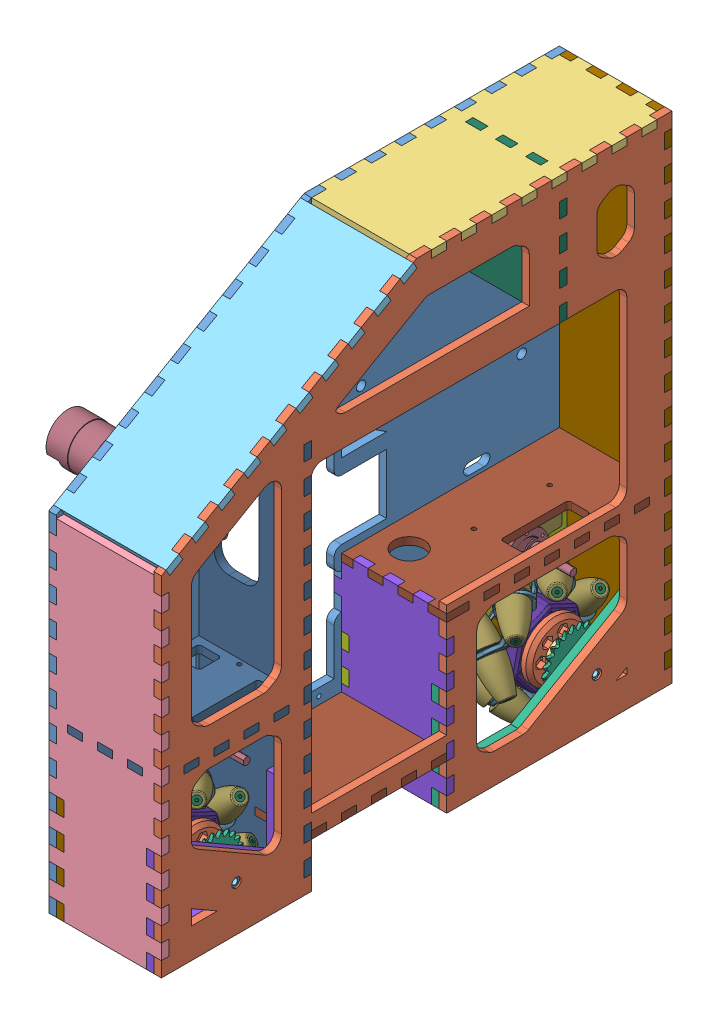
SolidWorks assembly Left Side Assembly, configuration Default. Lengths in mm.
Overall size (177.48 436.49 431.8).
170 component instances, 33 part files, 68 mates.
Components (placement in the parent):
- L Right Panel-1: L Right Panel [Default] at (153.5104 60.089 519.6166) size (6.35 419.1 431.8)
- L Left Panel-1: L Left Panel [Default] at (242.4104 60.089 519.6166) size (6.35 419.1 431.8)
- L Top Panel-1: L Top Panel [Default] at (153.5104 472.839 303.7166) size (95.25 6.35 215.9)
- L Front Panel-1: L Front Panel [Default] at (153.5104 60.089 513.2666) size (95.25 292.1 6.35)
- L Diag Panel-1: L Diag Panel [Default] at (153.5104 351.3271 512.48) x (1 0 0) z (0 0.866025 0.5) size (95.25 241.3 6.35)
- L Mecanum Back Plate A-1: L Mecanum Back Plate A [Default] at (242.4104 60.089 87.8166) x (0 0 1) z (-1 0 0) size (190.5 95.25 6.35)
- L Mecanum Back Plate B-1: L Mecanum Back Plate B [Default] at (166.2104 60.089 87.8166) x (0 0 1) z (-1 0 0) size (190.5 95.25 6.35)
- L Mecanum Front Plate A-1: L Mecanum Front Plate A [Default] at (236.0604 60.089 519.6166) x (0 0 -1) z (1 0 0) size (127 95.25 6.35)
- L Mecanum Front Plate B-1: L Mecanum Front Plate B [Default] at (166.2104 60.089 392.6166) x (0 0 1) z (-1 0 0) size (127 95.25 6.35)
- L Inside Front Panel A-1: L Inside Front Panel A [Default] at (153.5104 60.089 392.6166) size (95.25 355.6 6.35)
- L Bottom Panel-2: L Bottom Panel [Default] at (153.5104 98.189 398.9666) size (95.25 6.35 127)
- Mecanum Left Assembly-1: Mecanum Left Assembly [Default] at (127.408 133.3606 364.6681) x (0 -1 0) z (0 0 1) size (116.24 92.45 118.47)
  - Mecanum Left-1: Mecanum Left [Default] at (35.1717 68.1525 91.4485) size (116.24 62.26 118.47)
    - Roller-1: Roller [Default] at (-8.8714 -0.1061 -39.3041) x (-0.709843 -0.615883 -0.341777) z (0.144671 0.347402 -0.926489) size (22.31 28.6 22.31)
    - Washer-1: Washer [Default] at (-2.1949 -6.9473 -40.8283) x (-0.689398 -0.707107 0.15726) z (0.68937 -0.707107 -0.15738) size (6 6 6.25)
    - Bracket Left-1: Bracket Left [Default] at origin size (28.34 25.51 28.03)
    - Roller Hub-2: Roller Hub [Default] at (25.0439 -0.1061 31.5645) x (0.446415 -0.698084 -0.559815) z (0.703674 -0.112601 0.701544) size (15.2 28.65 15.2)
    - Pin-1: Pin [Default] at (40.2927 0.0354 -0.0424) x (0.491193 -0.615883 -0.615969) z (0.871051 0.347402 0.34725) size (2.6 61.8 2.6)
    - Roller-3: Roller [Default] at (-36.2516 0.1061 17.5878) x (-0.306866 0.707107 -0.637051) z (-0.900888 0.000087 0.434052) size (22.31 28.6 22.31)
    - Washer-2: Washer [Default] at (19.6895 6.9473 -35.8342) x (-0.552772 -0.707107 -0.440957) z (0.552849 -0.707107 0.44086) size (6 6 6.25)
    - Roller-5: Roller [Default] at (25.1987 -0.1061 -31.441) x (-0.175349 -0.615883 -0.768076) z (0.814571 0.347402 -0.464528) size (22.31 28.6 22.31)
    - Washer-5: Washer [Default] at (-33.2899 -6.9473 -23.7392) x (-0.306866 -0.707107 0.637051) z (0.306754 -0.707107 -0.637104) size (6 6 6.25)
    - Bracket Left-2: Bracket Left [Default] x (0.62347 0 -0.781847) z (0.781847 0 0.62347) size (28.34 25.51 28.03)
    - Pin-2: Pin [Default] at (25.1544 0.0354 31.4763) x (0.787838 -0.615883 0) z (0.271578 0.347402 0.897528) size (2.6 61.8 2.6)
    - Roller-6: Roller [Default] at (-36.3528 0.1061 -17.3777) x (0.306754 0.707107 -0.637104) z (-0.901039 0.000087 -0.433738) size (22.31 28.6 22.31)
    - Washer-6: Washer [Default] at (-15.741 6.9473 -37.7357) x (-0.689398 -0.707107 0.15726) z (0.68937 -0.707107 -0.15738) size (6 6 6.25)
    - Roller-9: Roller [Default] at (40.2927 -0.1061 0.099) x (0.491193 -0.615883 -0.615969) z (0.871051 0.347402 0.34725) size (22.31 28.6 22.31)
    - Washer-8: Washer [Default] at (-39.3157 -6.9473 11.2269) x (0.306754 -0.707107 0.637104) z (-0.306866 -0.707107 -0.637051) size (6 6 6.25)
    - Bracket Left-3: Bracket Left [Default] x (-0.22257 0 -0.974917) z (0.974917 0 -0.22257) size (28.34 25.51 28.03)
    - Bracket Left-4: Bracket Left [Default] x (-0.901001 0 -0.433816) z (0.433816 0 -0.901001) size (28.34 25.51 28.03)
    - Roller Hub-6: Roller Hub [Default] at (-36.2516 0.1061 17.5878) x (-0.446512 0.698084 -0.559737) z (-0.840471 -0.112601 0.530028) size (15.2 28.65 15.2)
    - Roller-10: Roller [Default] at (-9.0782 0.1061 -39.2568) x (0.68937 0.707107 -0.15738) z (-0.222655 0.000087 -0.974897) size (22.31 28.6 22.31)
    - Washer-10: Washer [Default] at (-39.3176 6.9473 -11.2201) x (-0.306866 -0.707107 0.637051) z (0.306754 -0.707107 -0.637104) size (6 6 6.25)
    - Roller-13: Roller [Default] at (25.0439 -0.1061 31.5645) x (0.787838 -0.615883 0) z (0.271578 0.347402 0.897528) size (22.31 28.6 22.31)
    - Washer-11: Washer [Default] at (-15.7344 -6.9473 37.7385) x (0.68937 -0.707107 0.15738) z (-0.689398 -0.707107 -0.15726) size (6 6 6.25)
    - Bracket Left-5: Bracket Left [Default] x (-0.900926 0 0.433974) z (-0.433974 0 -0.900926) size (28.34 25.51 28.03)
    - Roller Hub-8: Roller Hub [Default] at (-36.3437 -0.1061 17.3967) x (0.446512 -0.698084 0.559737) z (-0.840471 -0.112601 0.530028) size (15.2 28.65 15.2)
    - Roller-14: Roller [Default] at (25.0329 0.1061 -31.5732) x (0.552849 0.707107 0.44086) z (0.623402 0.000087 -0.781901) size (22.31 28.6 22.31)
    - Washer-14: Washer [Default] at (-33.2858 6.9473 23.745) x (0.306754 -0.707107 0.637104) z (-0.306866 -0.707107 -0.637051) size (6 6 6.25)
    - Roller Hub-11: Roller Hub [Default] at (25.1987 -0.1061 -31.441) x (-0.645131 -0.698084 -0.310619) z (0.527331 -0.112601 -0.842166) size (15.2 28.65 15.2)
    - Roller Hub-12: Roller Hub [Default] at (25.0329 0.1061 -31.5732) x (0.645131 0.698084 0.310619) z (0.527331 -0.112601 -0.842166) size (15.2 28.65 15.2)
    - Pin-5: Pin [Default] at (-8.9197 0.0354 39.293) x (0.491301 -0.615883 0.615883) z (-0.532275 0.347402 0.772007) size (2.6 61.8 2.6)
    - Washer-15: Washer [Default] at (19.6958 -6.9473 35.8307) x (0.552849 -0.707107 -0.44086) z (-0.552772 -0.707107 0.440957) size (6 6 6.25)
    - Bracket Left-6: Bracket Left [Default] x (-0.222399 0 0.974956) z (-0.974956 0 -0.222399) size (28.34 25.51 28.03)
    - Roller Hub-13: Roller Hub [Default] at (40.2927 -0.1061 0.099) x (-0.159363 -0.698084 -0.698056) z (0.98722 -0.112601 -0.112773) size (15.2 28.65 15.2)
    - Roller Hub-14: Roller Hub [Default] at (-36.3528 0.1061 -17.3777) x (0.159242 0.698084 -0.698084) z (-0.938409 -0.112601 -0.326663) size (15.2 28.65 15.2)
    - Roller-17: Roller [Default] at (40.2927 0.1061 -0.1131) x (0 0.707107 0.707107) z (1 0.000087 -0.000087) size (22.31 28.6 22.31)
    - Washer-17: Washer [Default] at (-2.1877 6.9473 40.8287) x (0.68937 -0.707107 0.15738) z (-0.689398 -0.707107 -0.15726) size (6 6 6.25)
    - Roller Hub-17: Roller Hub [Default] at (40.2927 0.1061 -0.1131) x (0.159363 0.698084 0.698056) z (0.98722 -0.112601 -0.112773) size (15.2 28.65 15.2)
    - Pin-7: Pin [Default] at (-36.2823 0.0354 17.5241) x (-0.175215 -0.615883 0.768107) z (-0.935449 0.347402 0.065166) size (2.6 61.8 2.6)
    - Washer-19: Washer [Default] at (40.2939 -6.9473 6.9403) x (0 -0.707107 -0.707107) z (0.000123 -0.707107 0.707107) size (6 6 6.25)
    - Bracket Left-7: Bracket Left [Default] x (0.623607 0 0.781738) z (-0.781738 0 0.623607) size (28.34 25.51 28.03)
    - Roller Hub-18: Roller Hub [Default] at (-36.2608 -0.1061 -17.5689) x (-0.159242 -0.698084 0.698084) z (-0.938409 -0.112601 -0.326663) size (15.2 28.65 15.2)
    - Roller-20: Roller [Default] at (-9.0576 -0.1061 39.2616) x (0.491301 -0.615883 0.615883) z (-0.532275 0.347402 0.772007) size (22.31 28.6 22.31)
    - Washer-20: Washer [Default] at (30.5578 6.9473 27.1659) x (0.552849 -0.707107 -0.44086) z (-0.552772 -0.707107 0.440957) size (6 6 6.25)
    - Pin-9: Pin [Default] at (-36.3221 0.0354 -17.4414) x (-0.709783 -0.615883 0.341901) z (-0.634175 0.347402 -0.690749) size (2.6 61.8 2.6)
    - Hub Inner Left-1: Hub Inner Left [Default] at origin size (62.26 19.81 61.13)
    - Roller Hub-21: Roller Hub [Default] at (-9.0645 -0.1061 39.26) x (0.716016 -0.698084 0) z (-0.109781 -0.112601 0.987557) size (15.2 28.65 15.2)
    - Roller Hub-22: Roller Hub [Default] at (-8.8577 0.1061 39.3072) x (-0.716016 0.698084 0) z (-0.109781 -0.112601 0.987557) size (15.2 28.65 15.2)
    - Roller Hub-23: Roller Hub [Default] at (-9.0782 0.1061 -39.2568) x (0.645077 0.698084 -0.310732) z (-0.329669 -0.112601 -0.937358) size (15.2 28.65 15.2)
    - Roller-22: Roller [Default] at (-36.3437 -0.1061 17.3967) x (-0.175215 -0.615883 0.768107) z (-0.935449 0.347402 0.065166) size (22.31 28.6 22.31)
    - Washer-23: Washer [Default] at (40.2915 6.9473 -6.9544) x (0 -0.707107 -0.707107) z (0.000123 -0.707107 0.707107) size (6 6 6.25)
    - Roller Hub-24: Roller Hub [Default] at (25.2097 0.1061 31.4322) x (-0.446415 0.698084 0.559815) z (0.703674 -0.112601 0.701544) size (15.2 28.65 15.2)
    - Pin-11: Pin [Default] at (-9.0092 0.0354 -39.2726) x (-0.709843 -0.615883 -0.341777) z (0.144671 0.347402 -0.926489) size (2.6 61.8 2.6)
    - Roller-24: Roller [Default] at (25.2152 0.1061 31.4278) x (-0.552772 0.707107 0.440957) z (0.623675 0.000087 0.781684) size (22.31 28.6 22.31)
    - Roller Hub-27: Roller Hub [Default] at (-8.8714 -0.1061 -39.3041) x (-0.645077 -0.698084 0.310732) z (-0.329669 -0.112601 -0.937358) size (15.2 28.65 15.2)
    - Roller-25: Roller [Default] at (-36.2608 -0.1061 -17.5689) x (-0.709783 -0.615883 0.341901) z (-0.634175 0.347402 -0.690749) size (22.31 28.6 22.31)
    - Washer-26: Washer [Default] at (30.553 -6.9473 -27.1713) x (-0.552772 -0.707107 -0.440957) z (0.552849 -0.707107 0.44086) size (6 6 6.25)
    - Hub Outer Left-1: Hub Outer Left [Default] at origin size (61.9 23.71 60.76)
    - Pin-13: Pin [Default] at (25.0881 0.0354 -31.5291) x (-0.175349 -0.615883 -0.768076) z (0.814571 0.347402 -0.464528) size (2.6 61.8 2.6)
    - Roller-28: Roller [Default] at (-8.8508 0.1061 39.3087) x (-0.689398 0.707107 -0.15726) z (-0.222314 0.000087 0.974975) size (22.31 28.6 22.31)
  - Mecanum Hub A-1: Mecanum Hub A [Default] at (35.1717 56.1525 91.4485) x (1 0 0) z (0 -1 0) size (50 50 12)
  - Mecanum Hub B-1: Mecanum Hub B [Default] at (35.1717 80.1525 91.4485) x (1 0 0) z (0 -1 0) size (50 50 12)
  - Tetrix Axle Hub-1: Tetrix Axle Hub [Default] at (35.1717 89.1525 91.4485) x (1 0 0) z (0 -1 0) size (22.1 22.1 9.5)
    - Tetrix Axle Hub Body-1: Tetrix Axle Hub Body [Default] at origin size (22.1 22.1 9.5)
    - Tetrix Axle Hub Set Screw-1: Tetrix Axle Hub Set Screw [Default] at (6.9308 6.9308 -3.325) x (-0.707107 0.707107 0) z (0 0 1) size (4.83 7.94 4.83)
  - Tetrix Axle Hub-2: Tetrix Axle Hub [Default] at (35.1717 47.1525 91.4485) x (1 0 0) z (0 1 0) size (22.1 22.1 9.5)
    - Tetrix Axle Hub Body-1: Tetrix Axle Hub Body [Default] at origin size (22.1 22.1 9.5)
    - Tetrix Axle Hub Set Screw-1: Tetrix Axle Hub Set Screw [Default] at (6.9308 6.9308 -3.325) x (-0.707107 0.707107 0) z (0 0 1) size (4.83 7.94 4.83)
  - Tetrix Bushing Bronze-1: Tetrix Bushing Bronze [Default] at (35.1717 40.4025 91.4485) x (-0.837169 0 -0.546944) z (-0.546944 0 0.837169) size (9.56 12.71 9.56)
  - Tetrix Bushing Bronze-2: Tetrix Bushing Bronze [Default] at (35.1717 104.3025 91.4485) x (-0.837169 0 -0.546944) z (-0.546944 0 0.837169) size (9.56 12.71 9.56)
  - Tetrix Bushing Bronze-3: Tetrix Bushing Bronze [Default] at (35.1717 107.4275 91.4485) x (0.996434 0 -0.084371) z (0.084371 0 0.996434) size (9.56 12.71 9.56)
  - Tetrix Sprocket 24T-1: Tetrix Sprocket 24T [Default] at (35.1717 99.9025 91.4485) x (1 0 0) z (0 -1 0) size (52 52 6.8)
  - Tetrix Axle Spacer Small-1: Tetrix Axle Spacer Small [Default] at (35.1717 105.865 91.4485) x (1 0 0) z (0 -1 0) size (9.5 9.5 3.12)
- Mecanum Left Assembly-2: Mecanum Left Assembly [Default] at (127.408 133.3606 59.8681) x (0 -1 0) z (0 0 1) size (116.24 92.45 118.47)
  - Mecanum Left-1: Mecanum Left [Default] at (35.1717 68.1525 91.4485) size (116.24 62.26 118.47)
    - Roller-1: Roller [Default] at (-8.8714 -0.1061 -39.3041) x (-0.709843 -0.615883 -0.341777) z (0.144671 0.347402 -0.926489) size (22.31 28.6 22.31)
    - Washer-1: Washer [Default] at (-2.1949 -6.9473 -40.8283) x (-0.689398 -0.707107 0.15726) z (0.68937 -0.707107 -0.15738) size (6 6 6.25)
    - Bracket Left-1: Bracket Left [Default] at origin size (28.34 25.51 28.03)
    - Roller Hub-2: Roller Hub [Default] at (25.0439 -0.1061 31.5645) x (0.446415 -0.698084 -0.559815) z (0.703674 -0.112601 0.701544) size (15.2 28.65 15.2)
    - Pin-1: Pin [Default] at (40.2927 0.0354 -0.0424) x (0.491193 -0.615883 -0.615969) z (0.871051 0.347402 0.34725) size (2.6 61.8 2.6)
    - Roller-3: Roller [Default] at (-36.2516 0.1061 17.5878) x (-0.306866 0.707107 -0.637051) z (-0.900888 0.000087 0.434052) size (22.31 28.6 22.31)
    - Washer-2: Washer [Default] at (19.6895 6.9473 -35.8342) x (-0.552772 -0.707107 -0.440957) z (0.552849 -0.707107 0.44086) size (6 6 6.25)
    - Roller-5: Roller [Default] at (25.1987 -0.1061 -31.441) x (-0.175349 -0.615883 -0.768076) z (0.814571 0.347402 -0.464528) size (22.31 28.6 22.31)
    - Washer-5: Washer [Default] at (-33.2899 -6.9473 -23.7392) x (-0.306866 -0.707107 0.637051) z (0.306754 -0.707107 -0.637104) size (6 6 6.25)
    - Bracket Left-2: Bracket Left [Default] x (0.62347 0 -0.781847) z (0.781847 0 0.62347) size (28.34 25.51 28.03)
    - Pin-2: Pin [Default] at (25.1544 0.0354 31.4763) x (0.787838 -0.615883 0) z (0.271578 0.347402 0.897528) size (2.6 61.8 2.6)
    - Roller-6: Roller [Default] at (-36.3528 0.1061 -17.3777) x (0.306754 0.707107 -0.637104) z (-0.901039 0.000087 -0.433738) size (22.31 28.6 22.31)
    - Washer-6: Washer [Default] at (-15.741 6.9473 -37.7357) x (-0.689398 -0.707107 0.15726) z (0.68937 -0.707107 -0.15738) size (6 6 6.25)
    - Roller-9: Roller [Default] at (40.2927 -0.1061 0.099) x (0.491193 -0.615883 -0.615969) z (0.871051 0.347402 0.34725) size (22.31 28.6 22.31)
    - Washer-8: Washer [Default] at (-39.3157 -6.9473 11.2269) x (0.306754 -0.707107 0.637104) z (-0.306866 -0.707107 -0.637051) size (6 6 6.25)
    - Bracket Left-3: Bracket Left [Default] x (-0.22257 0 -0.974917) z (0.974917 0 -0.22257) size (28.34 25.51 28.03)
    - Bracket Left-4: Bracket Left [Default] x (-0.901001 0 -0.433816) z (0.433816 0 -0.901001) size (28.34 25.51 28.03)
    - Roller Hub-6: Roller Hub [Default] at (-36.2516 0.1061 17.5878) x (-0.446512 0.698084 -0.559737) z (-0.840471 -0.112601 0.530028) size (15.2 28.65 15.2)
    - Roller-10: Roller [Default] at (-9.0782 0.1061 -39.2568) x (0.68937 0.707107 -0.15738) z (-0.222655 0.000087 -0.974897) size (22.31 28.6 22.31)
    - Washer-10: Washer [Default] at (-39.3176 6.9473 -11.2201) x (-0.306866 -0.707107 0.637051) z (0.306754 -0.707107 -0.637104) size (6 6 6.25)
    - Roller-13: Roller [Default] at (25.0439 -0.1061 31.5645) x (0.787838 -0.615883 0) z (0.271578 0.347402 0.897528) size (22.31 28.6 22.31)
    - Washer-11: Washer [Default] at (-15.7344 -6.9473 37.7385) x (0.68937 -0.707107 0.15738) z (-0.689398 -0.707107 -0.15726) size (6 6 6.25)
    - Bracket Left-5: Bracket Left [Default] x (-0.900926 0 0.433974) z (-0.433974 0 -0.900926) size (28.34 25.51 28.03)
    - Roller Hub-8: Roller Hub [Default] at (-36.3437 -0.1061 17.3967) x (0.446512 -0.698084 0.559737) z (-0.840471 -0.112601 0.530028) size (15.2 28.65 15.2)
    - Roller-14: Roller [Default] at (25.0329 0.1061 -31.5732) x (0.552849 0.707107 0.44086) z (0.623402 0.000087 -0.781901) size (22.31 28.6 22.31)
    - Washer-14: Washer [Default] at (-33.2858 6.9473 23.745) x (0.306754 -0.707107 0.637104) z (-0.306866 -0.707107 -0.637051) size (6 6 6.25)
    - Roller Hub-11: Roller Hub [Default] at (25.1987 -0.1061 -31.441) x (-0.645131 -0.698084 -0.310619) z (0.527331 -0.112601 -0.842166) size (15.2 28.65 15.2)
    - Roller Hub-12: Roller Hub [Default] at (25.0329 0.1061 -31.5732) x (0.645131 0.698084 0.310619) z (0.527331 -0.112601 -0.842166) size (15.2 28.65 15.2)
    - Pin-5: Pin [Default] at (-8.9197 0.0354 39.293) x (0.491301 -0.615883 0.615883) z (-0.532275 0.347402 0.772007) size (2.6 61.8 2.6)
    - Washer-15: Washer [Default] at (19.6958 -6.9473 35.8307) x (0.552849 -0.707107 -0.44086) z (-0.552772 -0.707107 0.440957) size (6 6 6.25)
    - Bracket Left-6: Bracket Left [Default] x (-0.222399 0 0.974956) z (-0.974956 0 -0.222399) size (28.34 25.51 28.03)
    - Roller Hub-13: Roller Hub [Default] at (40.2927 -0.1061 0.099) x (-0.159363 -0.698084 -0.698056) z (0.98722 -0.112601 -0.112773) size (15.2 28.65 15.2)
    - Roller Hub-14: Roller Hub [Default] at (-36.3528 0.1061 -17.3777) x (0.159242 0.698084 -0.698084) z (-0.938409 -0.112601 -0.326663) size (15.2 28.65 15.2)
    - Roller-17: Roller [Default] at (40.2927 0.1061 -0.1131) x (0 0.707107 0.707107) z (1 0.000087 -0.000087) size (22.31 28.6 22.31)
    - Washer-17: Washer [Default] at (-2.1877 6.9473 40.8287) x (0.68937 -0.707107 0.15738) z (-0.689398 -0.707107 -0.15726) size (6 6 6.25)
    - Roller Hub-17: Roller Hub [Default] at (40.2927 0.1061 -0.1131) x (0.159363 0.698084 0.698056) z (0.98722 -0.112601 -0.112773) size (15.2 28.65 15.2)
    - Pin-7: Pin [Default] at (-36.2823 0.0354 17.5241) x (-0.175215 -0.615883 0.768107) z (-0.935449 0.347402 0.065166) size (2.6 61.8 2.6)
    - Washer-19: Washer [Default] at (40.2939 -6.9473 6.9403) x (0 -0.707107 -0.707107) z (0.000123 -0.707107 0.707107) size (6 6 6.25)
    - Bracket Left-7: Bracket Left [Default] x (0.623607 0 0.781738) z (-0.781738 0 0.623607) size (28.34 25.51 28.03)
    - Roller Hub-18: Roller Hub [Default] at (-36.2608 -0.1061 -17.5689) x (-0.159242 -0.698084 0.698084) z (-0.938409 -0.112601 -0.326663) size (15.2 28.65 15.2)
    - Roller-20: Roller [Default] at (-9.0576 -0.1061 39.2616) x (0.491301 -0.615883 0.615883) z (-0.532275 0.347402 0.772007) size (22.31 28.6 22.31)
    - Washer-20: Washer [Default] at (30.5578 6.9473 27.1659) x (0.552849 -0.707107 -0.44086) z (-0.552772 -0.707107 0.440957) size (6 6 6.25)
    - Pin-9: Pin [Default] at (-36.3221 0.0354 -17.4414) x (-0.709783 -0.615883 0.341901) z (-0.634175 0.347402 -0.690749) size (2.6 61.8 2.6)
    - Hub Inner Left-1: Hub Inner Left [Default] at origin size (62.26 19.81 61.13)
    - Roller Hub-21: Roller Hub [Default] at (-9.0645 -0.1061 39.26) x (0.716016 -0.698084 0) z (-0.109781 -0.112601 0.987557) size (15.2 28.65 15.2)
    - Roller Hub-22: Roller Hub [Default] at (-8.8577 0.1061 39.3072) x (-0.716016 0.698084 0) z (-0.109781 -0.112601 0.987557) size (15.2 28.65 15.2)
    - Roller Hub-23: Roller Hub [Default] at (-9.0782 0.1061 -39.2568) x (0.645077 0.698084 -0.310732) z (-0.329669 -0.112601 -0.937358) size (15.2 28.65 15.2)
    - Roller-22: Roller [Default] at (-36.3437 -0.1061 17.3967) x (-0.175215 -0.615883 0.768107) z (-0.935449 0.347402 0.065166) size (22.31 28.6 22.31)
    - Washer-23: Washer [Default] at (40.2915 6.9473 -6.9544) x (0 -0.707107 -0.707107) z (0.000123 -0.707107 0.707107) size (6 6 6.25)
    - Roller Hub-24: Roller Hub [Default] at (25.2097 0.1061 31.4322) x (-0.446415 0.698084 0.559815) z (0.703674 -0.112601 0.701544) size (15.2 28.65 15.2)
    - Pin-11: Pin [Default] at (-9.0092 0.0354 -39.2726) x (-0.709843 -0.615883 -0.341777) z (0.144671 0.347402 -0.926489) size (2.6 61.8 2.6)
    - Roller-24: Roller [Default] at (25.2152 0.1061 31.4278) x (-0.552772 0.707107 0.440957) z (0.623675 0.000087 0.781684) size (22.31 28.6 22.31)
    - Roller Hub-27: Roller Hub [Default] at (-8.8714 -0.1061 -39.3041) x (-0.645077 -0.698084 0.310732) z (-0.329669 -0.112601 -0.937358) size (15.2 28.65 15.2)
    - Roller-25: Roller [Default] at (-36.2608 -0.1061 -17.5689) x (-0.709783 -0.615883 0.341901) z (-0.634175 0.347402 -0.690749) size (22.31 28.6 22.31)
    - Washer-26: Washer [Default] at (30.553 -6.9473 -27.1713) x (-0.552772 -0.707107 -0.440957) z (0.552849 -0.707107 0.44086) size (6 6 6.25)
    - Hub Outer Left-1: Hub Outer Left [Default] at origin size (61.9 23.71 60.76)
    - Pin-13: Pin [Default] at (25.0881 0.0354 -31.5291) x (-0.175349 -0.615883 -0.768076) z (0.814571 0.347402 -0.464528) size (2.6 61.8 2.6)
    - Roller-28: Roller [Default] at (-8.8508 0.1061 39.3087) x (-0.689398 0.707107 -0.15726) z (-0.222314 0.000087 0.974975) size (22.31 28.6 22.31)
  - Mecanum Hub A-1: Mecanum Hub A [Default] at (35.1717 56.1525 91.4485) x (1 0 0) z (0 -1 0) size (50 50 12)
  - Mecanum Hub B-1: Mecanum Hub B [Default] at (35.1717 80.1525 91.4485) x (1 0 0) z (0 -1 0) size (50 50 12)
  - Tetrix Axle Hub-1: Tetrix Axle Hub [Default] at (35.1717 89.1525 91.4485) x (1 0 0) z (0 -1 0) size (22.1 22.1 9.5)
    - Tetrix Axle Hub Body-1: Tetrix Axle Hub Body [Default] at origin size (22.1 22.1 9.5)
    - Tetrix Axle Hub Set Screw-1: Tetrix Axle Hub Set Screw [Default] at (6.9308 6.9308 -3.325) x (-0.707107 0.707107 0) z (0 0 1) size (4.83 7.94 4.83)
  - Tetrix Axle Hub-2: Tetrix Axle Hub [Default] at (35.1717 47.1525 91.4485) x (1 0 0) z (0 1 0) size (22.1 22.1 9.5)
    - Tetrix Axle Hub Body-1: Tetrix Axle Hub Body [Default] at origin size (22.1 22.1 9.5)
    - Tetrix Axle Hub Set Screw-1: Tetrix Axle Hub Set Screw [Default] at (6.9308 6.9308 -3.325) x (-0.707107 0.707107 0) z (0 0 1) size (4.83 7.94 4.83)
  - Tetrix Bushing Bronze-1: Tetrix Bushing Bronze [Default] at (35.1717 40.4025 91.4485) x (-0.837169 0 -0.546944) z (-0.546944 0 0.837169) size (9.56 12.71 9.56)
  - Tetrix Bushing Bronze-2: Tetrix Bushing Bronze [Default] at (35.1717 104.3025 91.4485) x (-0.837169 0 -0.546944) z (-0.546944 0 0.837169) size (9.56 12.71 9.56)
  - Tetrix Bushing Bronze-3: Tetrix Bushing Bronze [Default] at (35.1717 107.4275 91.4485) x (0.996434 0 -0.084371) z (0.084371 0 0.996434) size (9.56 12.71 9.56)
  - Tetrix Sprocket 24T-1: Tetrix Sprocket 24T [Default] at (35.1717 99.9025 91.4485) x (1 0 0) z (0 -1 0) size (52 52 6.8)
  - Tetrix Axle Spacer Small-1: Tetrix Axle Spacer Small [Default] at (35.1717 105.865 91.4485) x (1 0 0) z (0 -1 0) size (9.5 9.5 3.12)
- L Inside Front Panel B-1: L Inside Front Panel B [Default] at (153.5104 60.089 271.9666) size (95.25 146.05 6.35)
- L Back Panel-2: L Back Panel [Default] at (248.7604 60.089 94.1666) x (-1 0 0) z (0 0 -1) size (95.25 419.1 6.35)
- L Inside Bottom Panel A-1: L Inside Bottom Panel A [Default] at (153.5104 199.789 87.8166) x (0 0 1) z (-1 0 0) size (127 6.35 95.25)
- L Inside Bottom Panel B-1: L Inside Bottom Panel B [Default] at (153.5104 199.789 87.8166) x (0 0 1) z (-1 0 0) size (190.5 6.35 95.25)
- Tetrix Motor Mount-1: Tetrix Motor Mount [Default] at (197.9604 177.289 434.9666) x (0 0 1) z (1 0 0) size (72 45 12.7)
- Tetrix Motor Mount-2: Tetrix Motor Mount [Default] at (197.9604 177.289 172.4666) x (0 0 -1) z (-1 0 0) size (72 45 12.7)
- Tetrix Motor NeveRest (AM-2964)-1: Tetrix Motor NeveRest (AM-2964) [Default] at (184.6604 177.289 434.9666) x (0 1 0) z (1 0 0) size (38 38 133.81)
- Tetrix Motor NeveRest (AM-2964)-2: Tetrix Motor NeveRest (AM-2964) [Default] at (184.6604 177.289 172.4666) x (0 -1 0) z (1 0 0) size (38 38 133.81)
- Tetrix Motor Mount-3: Tetrix Motor Mount [Default] at (166.2104 320.439 421.4666) x (0 1 0) z (1 0 0) size (72 45 12.7)
- Tetrix Motor NeveRest (AM-2964)-3: Tetrix Motor NeveRest (AM-2964) [Default] at (146.5604 320.439 421.4666) x (0 0.171959 0.985104) z (1 0 0) size (38 38 133.81)
- Tetrix Sprocket 16T-1: Tetrix Sprocket 16T [Default] at (185.8704 180.739 491.0416) x (0 0 -1) z (1 0 0) size (36 36 6.8)
- Tetrix Sprocket 24T-1: Tetrix Sprocket 24T [Default] at (185.8704 313.5432 422.6703) x (0 0.679018 0.734122) z (1 0 0) size (52 52 6.8)
- L Servo Mount-2: L Servo Mount [Default] at (248.7604 371.239 183.0666) x (0 0 -1) z (1 0 0) size (6.35 107.95 95.25)
Mates (geometry in assembly coordinates):
- Coincident1: coincident aligned: plane of L Right Panel-1 through (153.5104 60.089 519.6166) normal (-1 0 0); plane of L Top Panel-1 through (153.5104 479.189 303.7166) normal (-1 0 0)
- Coincident2: coincident anti-aligned: plane of L Right Panel-1 through (153.5104 472.839 151.3166) normal (0 1 0); plane of L Top Panel-1 through (153.5104 472.839 303.7166) normal (0 -1 0)
- Coincident3: coincident aligned: plane of L Right Panel-1 through (159.8604 479.189 87.8166) normal (0 0 -1); plane of L Top Panel-1 through (153.5104 479.189 87.8166) normal (0 0 -1)
- Coincident8: coincident anti-aligned: plane of L Left Panel-1 through (242.4104 60.089 519.6166) normal (-1 0 0); plane of L Top Panel-1 through (242.4104 472.839 138.6166) normal (1 0 0)
- Coincident9: coincident aligned: plane of L Left Panel-1 through (248.7604 479.189 303.7166) normal (0 1 0); plane of L Top Panel-1 through (153.5104 479.189 303.7166) normal (0 1 0)
- Coincident11: coincident aligned: plane of L Right Panel-1 through (159.8604 354.539 519.6166) normal (0 0.866025 0.5); plane of L Diag Panel-1 through (153.5104 356.8263 515.655) normal (0 0.866025 0.5)
- Coincident12: coincident anti-aligned: plane of L Left Panel-1 through (242.4104 477.4763 306.683) normal (0 -0.5 0.866025); plane of L Diag Panel-1 through (153.5104 477.4763 306.683) normal (0 0.5 -0.866025)
- Coincident13: coincident aligned: plane of L Left Panel-1 through (248.7604 60.089 519.6166) normal (1 0 0); plane of L Diag Panel-1 through (248.7604 356.8263 515.655) normal (1 0 0)
- Coincident14: coincident aligned: plane of L Left Panel-1 through (248.7604 60.089 519.6166) normal (0 0 1); plane of L Front Panel-1 through (153.5104 60.089 519.6166) normal (0 0 1)
- Coincident15: coincident aligned: plane of L Left Panel-1 through (248.7604 60.089 519.6166) normal (1 0 0); plane of L Front Panel-1 through (248.7604 60.089 519.6166) normal (1 0 0)
- Coincident16: coincident aligned: plane of L Left Panel-1 through (248.7604 60.089 392.6166) normal (0 -1 0); plane of L Front Panel-1 through (153.5104 60.089 519.6166) normal (0 -1 0)
- Coincident17: coincident anti-aligned: plane of L Right Panel-1 through (159.8604 60.089 519.6166) normal (1 0 0); plane of L Mecanum Back Plate B-1 through (159.8604 60.089 87.8166) normal (-1 0 0)
- Coincident20: coincident anti-aligned: plane of L Left Panel-1 through (242.4104 60.089 519.6166) normal (-1 0 0); plane of L Mecanum Back Plate A-1 through (242.4104 60.089 87.8166) normal (1 0 0)
- Coincident21: coincident aligned: plane of L Left Panel-1 through (248.7604 60.089 87.8166) normal (0 -1 0); plane of L Mecanum Back Plate A-1 through (236.0604 60.089 87.8166) normal (0 -1 0)
- Coincident24: coincident anti-aligned: plane of L Left Panel-1 through (242.4104 60.089 519.6166) normal (-1 0 0); plane of L Mecanum Front Plate A-1 through (242.4104 60.089 519.6166) normal (1 0 0)
- Coincident25: coincident aligned: plane of L Left Panel-1 through (248.7604 60.089 392.6166) normal (0 -1 0); plane of L Mecanum Front Plate A-1 through (242.4104 60.089 519.6166) normal (0 -1 0)
- Coincident26: coincident aligned: plane of L Front Panel-1 through (153.5104 60.089 519.6166) normal (0 0 1); plane of L Mecanum Front Plate A-1 through (242.4104 60.089 519.6166) normal (0 0 1)
- Coincident27: coincident anti-aligned: plane of L Right Panel-1 through (159.8604 60.089 519.6166) normal (1 0 0); plane of L Mecanum Front Plate B-1 through (159.8604 60.089 392.6166) normal (-1 0 0)
- Coincident28: coincident aligned: plane of L Right Panel-1 through (159.8604 60.089 392.6166) normal (0 -1 0); plane of L Mecanum Front Plate B-1 through (159.8604 60.089 392.6166) normal (0 -1 0)
- Coincident29: coincident aligned: plane of L Front Panel-1 through (153.5104 60.089 519.6166) normal (0 0 1); plane of L Mecanum Front Plate B-1 through (159.8604 60.089 519.6166) normal (0 0 1)
- Coincident33: coincident aligned: plane of L Left Panel-1 through (248.7604 60.089 392.6166) normal (0 -1 0); plane of L Inside Front Panel A-1 through (153.5104 60.089 398.9666) normal (0 -1 0)
- Coincident34: coincident aligned: plane of L Left Panel-1 through (248.7604 60.089 519.6166) normal (1 0 0); plane of L Inside Front Panel A-1 through (248.7604 60.089 398.9666) normal (1 0 0)
- Coincident35: coincident anti-aligned: plane of L Left Panel-1 through (242.4104 72.789 398.9666) normal (0 0 -1); plane of L Inside Front Panel A-1 through (153.5104 60.089 398.9666) normal (0 0 1)
- Coincident39: coincident aligned: plane of L Left Panel-1 through (248.7604 98.189 278.3166) normal (0 -1 0); plane of L Bottom Panel-2 through (153.5104 98.189 398.9666) normal (0 -1 0)
- Coincident40: coincident aligned: plane of L Left Panel-1 through (248.7604 60.089 519.6166) normal (1 0 0); plane of L Bottom Panel-2 through (248.7604 104.539 398.9666) normal (1 0 0)
- Coincident41: coincident anti-aligned: plane of L Inside Front Panel A-1 through (153.5104 60.089 392.6166) normal (0 0 -1); plane of L Bottom Panel-2 through (248.7604 98.189 392.6166) normal (0 0 1)
- Concentric1: concentric anti-aligned: cylinder of L Left Panel-1 through (242.4104 98.189 456.1166) axis (1 0 0) radius 3.9688; cylinder of Mecanum Left Assembly-1/Tetrix Bushing Bronze-3 through (234.8354 98.189 456.1166) axis (-1 0 0) radius 4
- Coincident42: coincident anti-aligned: plane of L Mecanum Front Plate B-1 through (166.2104 60.089 392.6166) normal (1 0 0); plane of Mecanum Left Assembly-1/Tetrix Bushing Bronze-1 through (166.2104 94.8403 458.3044) normal (-1 0 0)
- Concentric2: concentric aligned: cylinder of L Right Panel-1 through (153.5104 98.189 151.3166) axis (1 0 0) radius 3.9688; cylinder of Mecanum Left Assembly-2/Tetrix Bushing Bronze-1 through (167.8104 98.189 151.3166) axis (1 0 0) radius 4
- Coincident43: coincident anti-aligned: plane of L Mecanum Back Plate B-1 through (166.2104 60.089 87.8166) normal (1 0 0); plane of Mecanum Left Assembly-2/Tetrix Bushing Bronze-1 through (166.2104 94.8403 153.5044) normal (-1 0 0)
- Coincident47: coincident aligned: plane of L Left Panel-1 through (248.7604 60.089 278.3166) normal (0 0 1); plane of L Inside Front Panel B-1 through (153.5104 60.089 278.3166) normal (0 0 1)
- Coincident48: coincident aligned: plane of L Left Panel-1 through (248.7604 60.089 519.6166) normal (1 0 0); plane of L Inside Front Panel B-1 through (248.7604 60.089 278.3166) normal (1 0 0)
- Coincident49: coincident aligned: plane of L Mecanum Back Plate A-1 through (236.0604 60.089 87.8166) normal (0 -1 0); plane of L Inside Front Panel B-1 through (153.5104 60.089 278.3166) normal (0 -1 0)
- Coincident50: coincident aligned: plane of L Left Panel-1 through (248.7604 479.189 87.8166) normal (0 0 -1); plane of L Back Panel-2 through (248.7604 60.089 87.8166) normal (0 0 -1)
- Coincident51: coincident aligned: plane of L Top Panel-1 through (153.5104 479.189 303.7166) normal (0 1 0); plane of L Back Panel-2 through (248.7604 479.189 87.8166) normal (0 1 0)
- Coincident52: coincident aligned: plane of L Left Panel-1 through (248.7604 60.089 519.6166) normal (1 0 0); plane of L Back Panel-2 through (248.7604 60.089 87.8166) normal (1 0 0)
- Coincident53: coincident aligned: plane of L Front Panel-1 through (153.5104 60.089 519.6166) normal (0 0 1); plane of L Inside Bottom Panel A-1 through (153.5104 206.139 519.6166) normal (0 0 1)
- Coincident54: coincident aligned: plane of L Left Panel-1 through (248.7604 60.089 519.6166) normal (1 0 0); plane of L Inside Bottom Panel A-1 through (248.7604 206.139 87.8166) normal (1 0 0)
- Coincident55: coincident anti-aligned: plane of L Left Panel-1 through (242.4104 206.139 475.1666) normal (0 -1 0); plane of L Inside Bottom Panel A-1 through (153.5104 206.139 87.8166) normal (0 1 0)
- Coincident56: coincident aligned: plane of L Left Panel-1 through (248.7604 60.089 519.6166) normal (1 0 0); plane of L Inside Bottom Panel B-1 through (248.7604 206.139 87.8166) normal (1 0 0)
- Coincident57: coincident aligned: plane of L Back Panel-2 through (248.7604 60.089 87.8166) normal (0 0 -1); plane of L Inside Bottom Panel B-1 through (153.5104 206.139 87.8166) normal (0 0 -1)
- Coincident59: coincident anti-aligned: plane of L Inside Bottom Panel A-1 through (153.5104 199.789 87.8166) normal (0 -1 0); plane of Tetrix Motor Mount-1 through (191.6104 199.789 398.9666) normal (0 1 0)
- Coincident60: coincident anti-aligned: plane of L Inside Bottom Panel B-1 through (153.5104 199.789 87.8166) normal (0 -1 0); plane of Tetrix Motor Mount-2 through (204.3104 199.789 208.4666) normal (0 1 0)
- Concentric9: concentric aligned: cylinder of L Inside Bottom Panel B-1 through (197.9604 199.789 140.4666) axis (0 1 0) radius 1.75; cylinder of Tetrix Motor Mount-2 through (197.9604 177.289 140.4666) axis (0 1 0) radius 1.85
- Parallel1: parallel aligned: plane of L Left Panel-1 through (248.7604 60.089 519.6166) normal (1 0 0); plane of Tetrix Motor Mount-2 through (204.3104 177.289 172.4666) normal (1 0 0)
- Concentric10: concentric aligned: cylinder of L Inside Bottom Panel A-1 through (197.9604 199.789 466.9666) axis (0 1 0) radius 1.75; cylinder of Tetrix Motor Mount-1 through (197.9604 177.289 466.9666) axis (0 1 0) radius 1.85
- Parallel2: parallel anti-aligned: plane of L Left Panel-1 through (248.7604 60.089 519.6166) normal (1 0 0); plane of Tetrix Motor Mount-1 through (191.6104 177.289 434.9666) normal (-1 0 0)
- Concentric11: concentric anti-aligned: cylinder of Tetrix Motor Mount-1 through (190.3404 177.289 434.9666) axis (1 0 0) radius 18.5; cylinder of Tetrix Motor NeveRest (AM-2964)-1 through (210.6604 177.289 434.9666) axis (-1 0 0) radius 18.5
- Concentric12: concentric aligned: cylinder of Tetrix Motor Mount-2 through (205.5804 177.289 172.4666) axis (-1 0 0) radius 18.5; cylinder of Tetrix Motor NeveRest (AM-2964)-2 through (210.6604 177.289 172.4666) axis (-1 0 0) radius 18.5
- Coincident63: coincident aligned: plane of Tetrix Motor NeveRest (AM-2964)-1 through (109.6604 177.289 434.9666) normal (-1 0 0); plane of Tetrix Motor NeveRest (AM-2964)-2 through (109.6604 177.289 172.4666) normal (-1 0 0)
- Coincident65: coincident anti-aligned: plane of L Inside Front Panel A-1 through (153.5104 60.089 398.9666) normal (0 0 1); plane of Tetrix Motor Mount-3 through (159.8604 284.439 398.9666) normal (0 0 -1)
- Parallel3: parallel aligned: plane of L Left Panel-1 through (248.7604 60.089 519.6166) normal (1 0 0); plane of Tetrix Motor Mount-3 through (172.5604 320.439 421.4666) normal (1 0 0)
- Concentric13: concentric anti-aligned: cylinder of L Inside Front Panel A-1 through (166.2104 288.439 392.6166) axis (0 0 1) radius 1.75; cylinder of Tetrix Motor Mount-3 through (166.2104 288.439 429.6666) axis (0 0 -1) radius 1.85
- Parallel4: parallel anti-aligned: plane of L Left Panel-1 through (248.7604 60.089 519.6166) normal (1 0 0); plane of Tetrix Motor Mount-3 through (159.8604 320.439 421.4666) normal (-1 0 0)
- Concentric14: concentric anti-aligned: cylinder of Tetrix Motor Mount-3 through (158.5904 320.439 421.4666) axis (1 0 0) radius 18.5; cylinder of Tetrix Motor NeveRest (AM-2964)-3 through (172.5604 320.439 421.4666) axis (-1 0 0) radius 18.5
- Coincident68: coincident aligned: plane of Tetrix Motor Mount-3 through (172.5604 320.439 421.4666) normal (1 0 0); plane of Tetrix Motor NeveRest (AM-2964)-3 through (172.5604 320.439 421.4666) normal (1 0 0)
- Concentric15: concentric aligned: cylinder of Tetrix Motor NeveRest (AM-2964)-3 through (194.8604 313.5432 422.6703) axis (-1 0 0) radius 3; cylinder of Tetrix Sprocket 24T-1 through (189.8704 313.5432 422.6703) axis (-1 0 0) radius 11
- Coincident69: coincident aligned: plane of Tetrix Sprocket 16T-1 through (189.8704 180.739 491.0416) normal (1 0 0); plane of Tetrix Sprocket 24T-1 through (189.8704 313.5432 422.6703) normal (1 0 0)
- Distance3: distance = 3.81 mm anti-aligned: plane of Tetrix Motor NeveRest (AM-2964)-3 through (179.2604 313.5432 422.6703) normal (1 0 0); plane of Tetrix Sprocket 24T-1 through (183.0704 295.6857 439.1874) normal (-1 0 0)
- Coincident73: coincident aligned: plane of L Right Panel-1 through (159.8604 60.089 519.6166) normal (0 0 1); plane of L Front Panel-1 through (153.5104 60.089 519.6166) normal (0 0 1)
- Coincident84: coincident aligned: plane of L Top Panel-1 through (153.5104 479.189 303.7166) normal (-1 0 0); plane of L Servo Mount-2 through (153.5104 371.239 176.7166) normal (-1 0 0)
- Coincident85: coincident aligned: plane of L Top Panel-1 through (153.5104 479.189 303.7166) normal (0 1 0); plane of L Servo Mount-2 through (248.7604 479.189 176.7166) normal (0 1 0)
- Coincident88: coincident anti-aligned: plane of L Left Panel-1 through (242.4104 434.739 176.7166) normal (0 0 1); plane of L Servo Mount-2 through (248.7604 371.239 176.7166) normal (0 0 -1)
- Coincident89: coincident anti-aligned: plane of L Left Panel-1 through (242.4104 199.789 271.9666) normal (0 1 0); plane of L Inside Bottom Panel B-1 through (153.5104 199.789 87.8166) normal (0 -1 0)
- Parallel5: parallel anti-aligned: plane of L Front Panel-1 through (153.5104 60.089 513.2666) normal (0 0 -1); plane of Tetrix Motor NeveRest (AM-2964)-1 through (220.9604 173.5738 444.4666) normal (0 0 1)
- Parallel6: parallel anti-aligned: plane of L Back Panel-2 through (248.7604 60.089 94.1666) normal (0 0 1); plane of Tetrix Motor NeveRest (AM-2964)-2 through (220.9604 181.0041 162.9666) normal (0 0 -1)
- Concentric16: concentric aligned: cylinder of L Right Panel-1 through (153.5104 180.739 491.0416) axis (1 0 0) radius 4; cylinder of Tetrix Sprocket 16T-1 through (183.0704 180.739 491.0416) axis (1 0 0) radius 4
- Distance4: distance = 6.35 mm aligned: plane of Tetrix Motor Mount-1 through (204.3104 177.289 434.9666) normal (1 0 0); plane of Tetrix Motor NeveRest (AM-2964)-1 through (210.6604 177.289 434.9666) normal (1 0 0)
